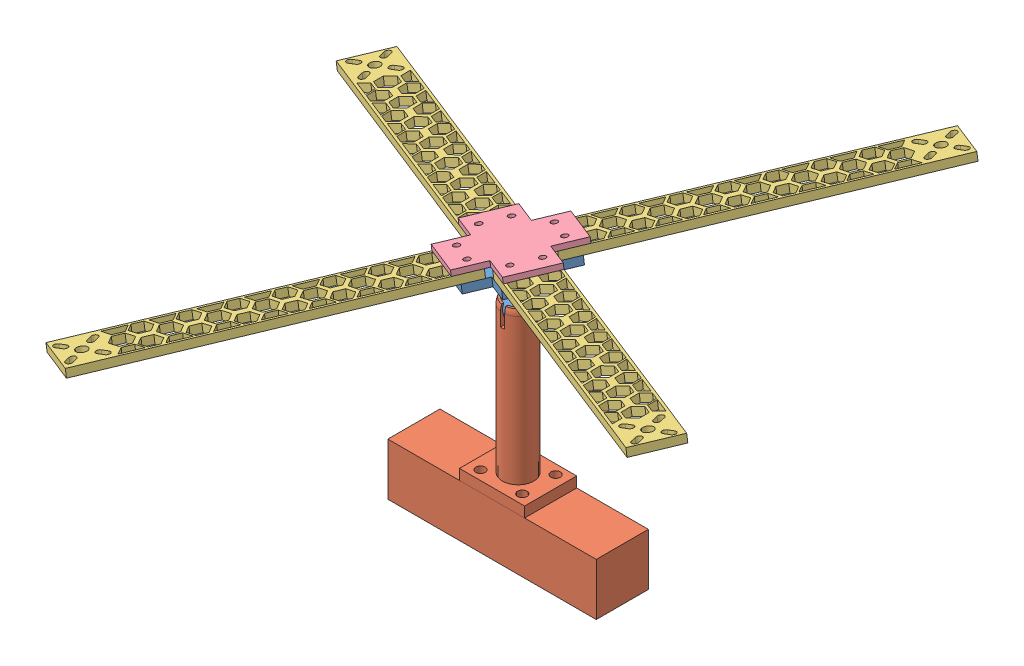
SolidWorks assembly Assem1, configuration Default. Lengths in mm.
Overall size (301.07 152.15 305.86).
7 component instances, 4 part files, 11 mates.
Components (placement in the parent):
- Ball Joint-1: Ball Joint [Default] at (14.1017 9.7387 35.4176) x (0.447996 0.054118 -0.892396) z (0.876376 0.170827 0.450314) size (44.45 24.79 44.45)
- Ball Joint Base-1: Ball Joint Base [Default] at (14.1017 -91.8613 35.4176) size (101.6 104.42 25.4)
- Test Arm-1: Test Arm [Default] at (50.9968 32.4795 -45.0124) x (-0.447996 -0.054118 0.892396) z (-0.876376 -0.170827 -0.450314) size (152.4 3.81 22.1)
- Test Arm-2: Test Arm [Default] at (-67.5809 12.339 -5.4306) x (0.876376 0.170827 0.450314) z (-0.447996 -0.054118 0.892396) size (152.4 3.81 22.1)
- Test Arm-3: Test Arm [Default] at (89.3518 42.9291 75.2071) x (-0.876376 -0.170827 -0.450314) z (0.447996 0.054118 -0.892396) size (152.4 3.81 22.1)
- Test Arm-4: Test Arm [Default] at (-29.2259 22.7886 114.7889) x (0.447996 0.054118 -0.892396) z (0.876376 0.170827 0.450314) size (152.4 3.81 22.1)
- Top Plate-1: Top Plate [Default] at (10.2118 31.3824 34.7774) x (0.876376 0.170827 0.450314) z (-0.447996 -0.054118 0.892396) size (50.8 2.54 50.8)
Mates (geometry in assembly coordinates):
- Coincident1: coincident aligned: circle of Ball Joint-1; circle of Test Arm-4
- Coincident3: coincident aligned: circle of Ball Joint-1; circle of Test Arm-3
- Coincident4: coincident aligned: circle of Ball Joint-1; circle of Test Arm-3
- Coincident5: coincident aligned: circle of Ball Joint-1; circle of Test Arm-1
- Coincident6: coincident aligned: circle of Ball Joint-1; circle of Test Arm-1
- Coincident7: coincident aligned: circle of Ball Joint-1; circle of Test Arm-2
- Coincident8: coincident aligned: circle of Ball Joint-1; circle of Test Arm-2
- Coincident9: coincident aligned: circle of Ball Joint-1; circle of Test Arm-4
- Concentric3: concentric: sphere of Ball Joint-1; sphere of Ball Joint Base-1
- Coincident12: coincident aligned: circle of Test Arm-3; circle of Top Plate-1
- Coincident13: coincident aligned: circle of Test Arm-1; circle of Top Plate-1
